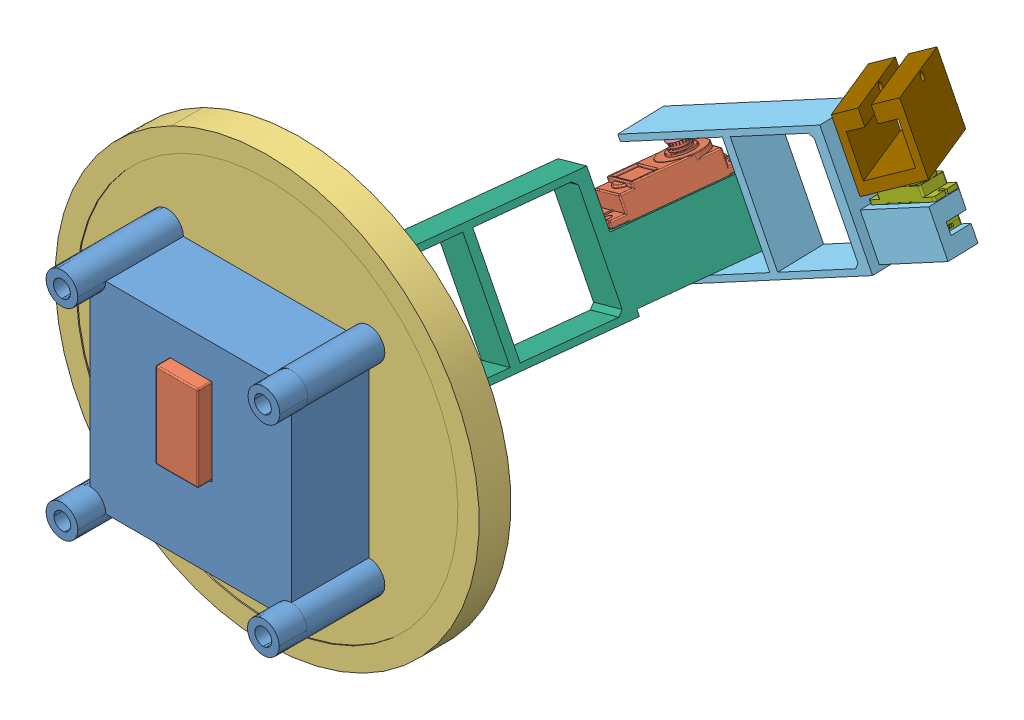
SolidWorks assembly base_servo, configuration Default. Lengths in mm.
Overall size (284.28 268.79 258.09).
13 component instances, 9 part files, 32 mates.
Components (placement in the parent):
- base-1: base [Default] at (-355.248 107.8843 138.3056) size (110.28 110 49.82)
- Servo MG996R-1: Servo MG996R [Predeterminado] at (-317.748 51.5343 181.5156) x (0 1 0) z (-1 0 0) size (53.6 47.6 20)
- base_tournante-1: base_tournante [Default] at (-307.748 61.5343 138.8156) x (-0.451903 0.892067 0) z (-0.892067 -0.451903 0) size (200 71 200)
- access-1: access [Default] at (-307.748 61.5343 138.4156) x (0.256384 0.966575 0) z (0 0 -1) size (20 20 6.5)
- Servo MG996R-2: Servo MG996R [Predeterminado] at (-305.823 35.6056 75.4656) x (0 0 1) z (-0.892067 -0.451903 0) size (53.6 47.6 20)
- avant_bras-1: avant_bras [Default] at (-278.4497 43.2509 -43.7653) x (-0.451903 0.892067 0) z (-0.055999 -0.028368 -0.998028) size (55 134 23)
- bras-1: bras [Default] at (-308.2009 28.9082 96.7701) x (-0.451903 0.892067 0) z (-0.858403 -0.43485 -0.27212) size (55 155 23)
- access-2: access [Default] at (-286.1425 93.1615 -33.2296) x (0.797764 0.404131 0.447494) z (-0.451903 0.892067 0) size (20 20 6.5)
- access-3: access [Default] at (-316.3794 78.5727 85.4656) x (-0.729371 -0.369485 -0.575759) z (-0.451903 0.892067 0) size (20 20 6.5)
- Servo MG996R-3: Servo MG996R [Predeterminado] at (-272.822 51.5946 -45.5734) x (-0.24275 -0.122972 0.962263) z (-0.858403 -0.43485 -0.27212) size (53.6 47.6 20)
- SG90 - Micro Servo 9g - Tower Pro.1-1: SG90 - Micro Servo 9g - Tower Pro.1 [Peça] at (-181.0509 110.7823 -42.5931) x (-0.890308 -0.451012 0.062775) z (-0.055999 -0.028368 -0.998028) size (32.1 29.95 12.4)
- SG90 - Micro Servo 9g - Tower Pro.4-1: SG90 - Micro Servo 9g - Tower Pro.4 [Peça] at (-186.001 131.9277 -42.9164) x (0.4871 0.246755 0.837762) z (-0.74734 -0.378587 0.546035) size (34.5 3.8 16.7)
- Stylet-1: Stylet [Default] at (-181.4203 130.8852 -14.4402) x (-0.451903 0.892067 0) z (-0.4871 -0.246755 -0.837762) size (30 25 50)
Mates (geometry in assembly coordinates):
- Parallel5: parallel aligned: plane of base-1 through (-355.248 107.8843 174.9156) normal (0 0 1); plane of Servo MG996R-1 through (-297.748 51.5343 181.5156) normal (0 0 1)
- Parallel6: parallel anti-aligned: plane of base-1 through (-267.748 107.8843 138.3056) normal (0 1 0); plane of Servo MG996R-1 through (-317.748 51.5343 144.9156) normal (0 -1 0)
- Coincident9: coincident anti-aligned: plane of base-1 through (-297.748 98.3843 154.9156) normal (0 0 -1); plane of Servo MG996R-1 through (-317.748 98.4843 154.9156) normal (0 0 1)
- Coincident10: coincident anti-aligned: plane of base-1 through (-297.748 91.8343 174.9156) normal (0 -1 0); plane of Servo MG996R-1 through (-317.748 91.8343 144.9156) normal (0 1 0)
- Coincident11: coincident anti-aligned: plane of base-1 through (-297.748 98.3843 175.9156) normal (-1 0 0); plane of Servo MG996R-1 through (-297.748 51.5343 144.9156) normal (1 0 0)
- Parallel7: parallel anti-aligned: plane of base-1 through (-355.248 107.8843 138.3056) normal (0 0 -1); plane of base_tournante-1 through (-307.748 61.5343 138.3156) normal (0 0 1)
- Coincident15: coincident anti-aligned: plane of Servo MG996R-1 through (-307.748 61.5343 133.9156) normal (0 0 -1); plane of access-1 through (-307.748 61.5343 133.9156) normal (0 0 1)
- Coincident18: coincident anti-aligned: plane of base_tournante-1 through (-307.748 61.5343 131.9156) normal (0 0 1); plane of access-1 through (-307.748 61.5343 131.9156) normal (0 0 -1)
- Concentric1: concentric aligned: cylinder of base_tournante-1 through (-307.748 61.5343 131.9156) axis (0 0 1) radius 10.5; cylinder of access-1 through (-307.748 61.5343 131.9156) axis (0 0 1) radius 10
- Coincident22: coincident aligned: axis of Servo MG996R-1 through (-307.748 61.5343 134.2156) axis (0 0 1); line of base_tournante-1 through (-307.748 61.5343 123.8156) axis (0 0 1)
- Coincident26: coincident anti-aligned: plane of base_tournante-1 through (-305.823 35.6056 123.8156) normal (-0.451903 0.892067 0); plane of Servo MG996R-2 through (-287.9817 44.6437 75.4656) normal (0.451903 -0.892067 0)
- Coincident28: coincident anti-aligned: plane of base_tournante-1 through (-287.9817 44.6437 123.8156) normal (-0.892067 -0.451903 0); plane of Servo MG996R-2 through (-304.5213 77.2933 75.4656) normal (0.892067 0.451903 0)
- Distance1: distance = 1 mm anti-aligned: plane of Servo MG996R-2 through (-322.3627 68.2553 75.4656) normal (0 0 -1); plane of base_tournante-1 through (-305.823 35.6056 74.4656) normal (0 0 1)
- Coincident29: coincident anti-aligned: plane of Servo MG996R-2 through (-318.413 82.587 85.4656) normal (-0.451903 0.892067 0); plane of access-3 through (-318.413 82.587 85.4656) normal (0.451903 -0.892067 0)
- Coincident30: coincident aligned: line of Servo MG996R-2 through (-318.2774 82.3194 85.4656) axis (0.451903 -0.892067 0); line of access-3 through (-318.413 82.587 85.4656) axis (0.451903 -0.892067 0)
- Coincident31: coincident anti-aligned: plane of bras-1 through (-309.7684 89.2082 5.3551) normal (0.451903 -0.892067 0); plane of access-3 through (-319.3168 84.3712 85.4656) normal (-0.451903 0.892067 0)
- Coincident32: coincident anti-aligned: line of Servo MG996R-2 through (-318.2774 82.3194 85.4656) axis (0.451903 -0.892067 0); line of bras-1 through (-318.3 82.364 85.4656) axis (-0.451903 0.892067 0)
- Coincident33: coincident anti-aligned: plane of access-2 through (-288.1761 97.1758 -33.2296) normal (0.451903 -0.892067 0); plane of Servo MG996R-3 through (-288.1761 97.1758 -33.2296) normal (-0.451903 0.892067 0)
- Coincident34: coincident aligned: line of access-2 through (-288.1761 97.1758 -33.2296) axis (0.451903 -0.892067 0); line of Servo MG996R-3 through (-288.0405 96.9082 -33.2296) axis (0.451903 -0.892067 0)
- Coincident35: coincident anti-aligned: plane of bras-1 through (-267.3909 54.3459 6.3944) normal (-0.858403 -0.43485 -0.27212); plane of Servo MG996R-3 through (-272.1936 92.9413 -40.131) normal (0.858403 0.43485 0.27212)
- Coincident36: coincident anti-aligned: plane of bras-1 through (-322.1421 56.4284 96.7701) normal (-0.451903 0.892067 0); plane of Servo MG996R-3 through (-283.2283 76.1414 -51.9725) normal (0.451903 -0.892067 0)
- Coincident37: coincident anti-aligned: plane of bras-1 through (-272.822 51.5946 -45.5734) normal (-0.24275 -0.122972 0.962263); plane of Servo MG996R-3 through (-289.3617 84.2443 -45.5734) normal (0.24275 0.122972 -0.962263)
- Coincident38: coincident anti-aligned: plane of avant_bras-1 through (-218.4993 134.7147 -49.7289) normal (0.451903 -0.892067 0); plane of access-2 through (-289.0799 98.9599 -33.2296) normal (-0.451903 0.892067 0)
- Coincident39: coincident anti-aligned: line of avant_bras-1 through (-288.0631 96.9528 -33.2296) axis (-0.451903 0.892067 0); line of access-2 through (-289.0799 98.9599 -33.2296) axis (0.451903 -0.892067 0)
- Coincident40: coincident anti-aligned: plane of avant_bras-1 through (-165.0354 107.069 -37.2741) normal (-0.451903 0.892067 0); plane of SG90 - Micro Servo 9g - Tower Pro.1-1 through (-167.3181 105.9126 -48.4856) normal (0.451903 -0.892067 0)
- Distance2: distance = 1 mm anti-aligned: plane of avant_bras-1 through (-165.0354 107.069 -37.2741) normal (-0.890308 -0.451012 0.062775); plane of SG90 - Micro Servo 9g - Tower Pro.1-1 through (-173.6562 120.3014 -48.5389) normal (0.890308 0.451012 -0.062775)
- Coincident47: coincident anti-aligned: plane of avant_bras-1 through (-277.6299 43.6662 -29.1543) normal (-0.055999 -0.028368 -0.998028); plane of SG90 - Micro Servo 9g - Tower Pro.1-1 through (-173.7774 120.2401 -37.158) normal (0.055999 0.028368 0.998028)
- Coincident48: coincident anti-aligned: plane of SG90 - Micro Servo 9g - Tower Pro.1-1 through (-185.1875 130.3219 -42.9164) normal (-0.451903 0.892067 0); plane of SG90 - Micro Servo 9g - Tower Pro.4-1 through (-185.1875 130.3219 -42.9164) normal (0.451903 -0.892067 0)
- Coincident49: coincident anti-aligned: line of SG90 - Micro Servo 9g - Tower Pro.1-1 through (-185.0972 130.1435 -42.9164) axis (0.451903 -0.892067 0); line of SG90 - Micro Servo 9g - Tower Pro.4-1 through (-185.3683 130.6788 -42.9164) axis (-0.451903 0.892067 0)
- Coincident50: coincident anti-aligned: plane of SG90 - Micro Servo 9g - Tower Pro.4-1 through (-186.001 131.9277 -42.9164) normal (-0.451903 0.892067 0); plane of Stylet-1 through (-182.776 133.5614 -14.4402) normal (0.451903 -0.892067 0)
- Distance3: distance = 0.0309 mm: line of SG90 - Micro Servo 9g - Tower Pro.4-1 through (-192.4069 127.1132 -55.022) axis (-0.451903 0.892067 0); line of Stylet-1 through (-193.0248 128.3695 -54.9967) axis (0.451903 -0.892067 0)
- Coincident55: coincident anti-aligned: line of SG90 - Micro Servo 9g - Tower Pro.4-1 through (-177.1607 134.8366 -28.8001) axis (-0.451903 0.892067 0); line of Stylet-1 through (-177.7933 136.0855 -28.8001) axis (0.451903 -0.892067 0)
